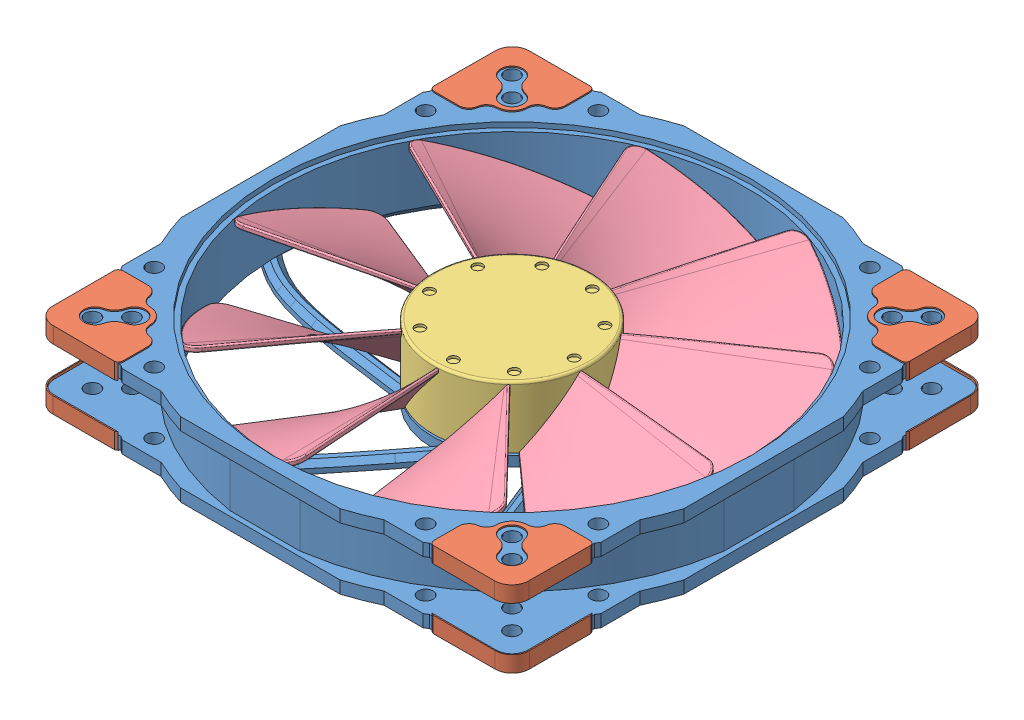
SolidWorks assembly NF-A20, configuration Standard. Lengths in mm.
Overall size (257.72 31.13 257.72).
21 component instances, 4 part files, 5 mates.
Components (placement in the parent):
- NF-A20-Caase-1: NF-A20-Caase [Standard] at origin size (204 31 204)
  - NF-A20-Case-1: NF-A20-Case [Standard] at (-102 -30.5 -102) size (204 30 204)
  - NF-A20-Rubber-Edge-1: NF-A20-Rubber-Edge [Standard] at (-101.5 -0.5 -101.5) x (0 0 1) z (1 0 0) size (33.51 6.5 33.5)
  - NF-A20-Rubber-Edge-2: NF-A20-Rubber-Edge [Standard] at (-101.5 -0.5 -102.5) x (1 0 0) z (0 0 -1) size (33.51 6.5 33.5)
  - NF-A20-Rubber-Edge-3: NF-A20-Rubber-Edge [Standard] at (-102.5 -0.5 -101.5) x (-1 0 0) z (0 0 1) size (33.51 6.5 33.5)
  - NF-A20-Rubber-Edge-4: NF-A20-Rubber-Edge [Standard] at (-102.5 -0.5 -102.5) x (0 0 -1) z (-1 0 0) size (33.51 6.5 33.5)
  - NF-A20-Rubber-Edge-5: NF-A20-Rubber-Edge [Standard] at (-102.5 -30.5 -102.5) x (-1 0 0) z (0 0 -1) size (33.51 6.5 33.5)
  - NF-A20-Rubber-Edge-6: NF-A20-Rubber-Edge [Standard] at (-101.5 -30.5 -102.5) x (0 0 -1) z (1 0 0) size (33.51 6.5 33.5)
  - NF-A20-Rubber-Edge-7: NF-A20-Rubber-Edge [Standard] at (-102.5 -30.5 -101.5) x (0 0 1) z (-1 0 0) size (33.51 6.5 33.5)
  - NF-A20-Rubber-Edge-8: NF-A20-Rubber-Edge [Standard] at (-101.5 -30.5 -101.5) size (33.51 6.5 33.5)
- NF-A20-Rotor-1: NF-A20-Rotor [Standard] at (-56.8129 -0.5 -99.5251) x (0.667379 0 0.744718) z (-0.744718 0 0.667379) size (214.05 28.34 214.61)
  - NF-A20-Rotor-Core-1: NF-A20-Rotor-Core [Standard] at (-32 -30 32) x (0.999376 0 -0.035329) z (0.035329 0 0.999376) size (64 25 64)
  - NF-A20-Rotor-Fin-1: NF-A20-Rotor-Fin [Standard] at (-33.0712 -30.212 32.0423) x (0.970961 -0.007209 0.239128) z (-0.23919 -0.009447 0.970927) size (68.87 27.34 53.71)
  - NF-A20-Rotor-Fin-2: NF-A20-Rotor-Fin [Standard] at (-32.8478 -30.212 31.3438) x (0.590091 -0.007209 0.807305) z (-0.80733 -0.009447 0.590025) size (68.87 27.34 53.71)
  - NF-A20-Rotor-Fin-3: NF-A20-Rotor-Fin [Standard] at (-32.2277 -30.212 30.9524) x (-0.06689 -0.007209 0.997734) z (-0.997711 -0.009447 -0.066957) size (68.87 27.34 53.71)
  - NF-A20-Rotor-Fin-4: NF-A20-Rotor-Fin [Standard] at (-31.501 -30.212 31.0512) x (-0.692572 -0.007209 0.721313) z (-0.721252 -0.009447 -0.692608) size (68.87 27.34 53.71)
  - NF-A20-Rotor-Fin-5: NF-A20-Rotor-Fin [Standard] at (-31.0079 -30.212 31.5939) x (-0.994192 -0.007209 0.107381) z (-0.107311 -0.009447 -0.994181) size (68.87 27.34 53.71)
  - NF-A20-Rotor-Fin-6: NF-A20-Rotor-Fin [Standard] at (-30.9789 -30.212 32.3266) x (-0.830618 -0.007209 -0.556796) z (0.556842 -0.009447 -0.830565) size (68.87 27.34 53.71)
  - NF-A20-Rotor-Fin-7: NF-A20-Rotor-Fin [Standard] at (-31.4278 -30.212 32.9066) x (-0.278389 -0.007209 -0.960441) z (0.960442 -0.009447 -0.278319) size (68.87 27.34 53.71)
  - NF-A20-Rotor-Fin-8: NF-A20-Rotor-Fin [Standard] at (-32.1444 -30.212 33.0623) x (0.404101 -0.007209 -0.914686) z (0.914641 -0.009447 0.404156) size (68.87 27.34 53.71)
  - NF-A20-Rotor-Fin-9: NF-A20-Rotor-Fin [Standard] at (-32.7934 -30.212 32.7209) x (0.897508 -0.007209 -0.440939) z (0.440869 -0.009447 0.897522) size (68.87 27.34 53.71)
Mates (geometry in assembly coordinates):
- Deckungsgleich1: coincident aligned: plane of NF-A20-Caase-1/NF-A20-Case-1 through (-134.3265 -30.5 0) normal (0 0 1); plane of assembly through (0 0 0) normal (0 0 1)
- Deckungsgleich2: coincident aligned: plane of NF-A20-Caase-1/NF-A20-Case-1 through (0 -30.5 -69.6735) normal (1 0 0); plane of assembly through (0 0 0) normal (1 0 0)
- Deckungsgleich3: coincident aligned: plane of NF-A20-Caase-1/NF-A20-Rubber-Edge-8 through (-181.7472 0 -181.75) normal (0 1 0); plane of assembly through (0 0 0) normal (0 1 0)
- Konzentrisch1: concentric aligned: cylinder of NF-A20-Caase-1/NF-A20-Case-1 through (-102 -30.5 -102) axis (0 1 0) radius 32; cylinder of NF-A20-Rotor-1/NF-A20-Rotor-Core-1 through (-102 -30.5 -102) axis (0 1 0) radius 32
- Abstand1: distance = 1 mm anti-aligned: plane of NF-A20-Rotor-1/NF-A20-Rotor-Core-1 through (-102 -25.5 -102) normal (0 -1 0); plane of NF-A20-Caase-1/NF-A20-Case-1 through (-43.3821 -26.5 -112.2216) normal (0 1 0)
